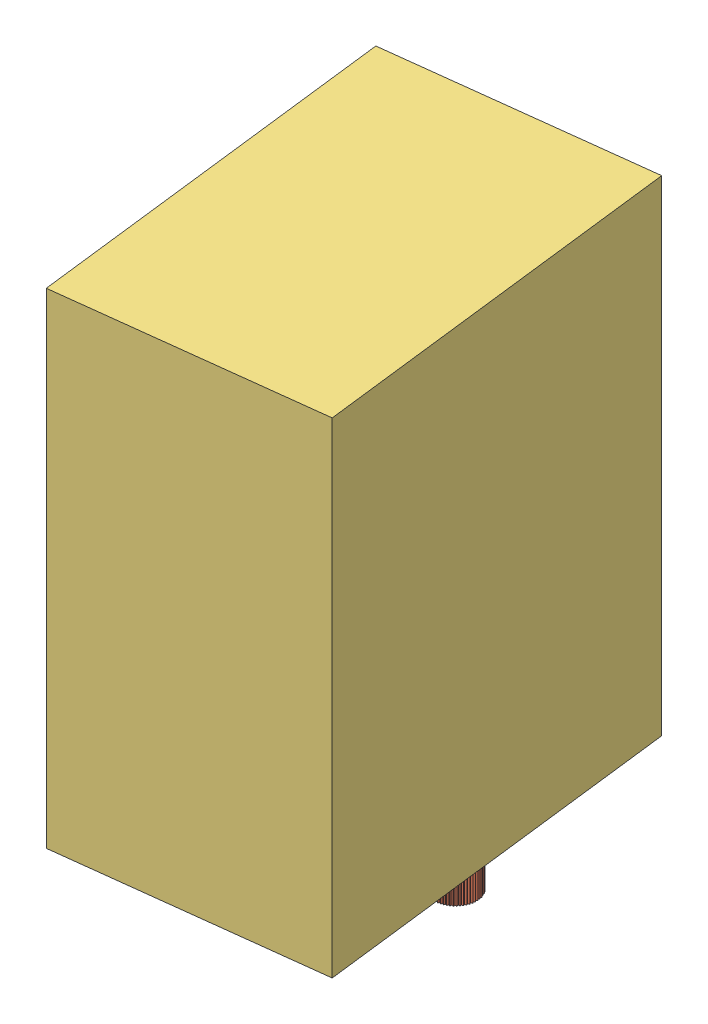
SolidWorks assembly Assembly for real, configuration Default. Lengths in mm.
Overall size (61.91 127.5 83.55).
4 component instances, 4 part files, 6 mates.
Components (placement in the parent):
- realpart-1: realpart [Default] at (4.0864 26.7845 46.9206) size (22.37 37 22.37)
- SmallerGear-1: SmallerGear [Default] at (2.4247 12.2845 33.1002) x (0.936342 0 -0.351089) z (0 -1 0) size (16 16 34.5)
- dstarrcomp-1: dstarrcomp [Default] at (9.5028 5.2845 91.9694) x (0 1 0) z (0.119374 0 0.992849) size (100 53 77.78)
- cover-1: cover [Default] at (-9.7757 45.7845 40.5297) x (0 -1 0) z (-0.992849 0 0.119374) size (22 20 37.19)
Mates (geometry in assembly coordinates):
- Concentric1: concentric anti-aligned: cylinder of realpart-1 through (4.0864 46.7845 46.9206) axis (0 -1 0) radius 8; cylinder of dstarrcomp-1 through (4.0864 23.7845 46.9206) axis (0 1 0) radius 8
- Coincident1: coincident anti-aligned: plane of realpart-1 through (4.0864 42.7845 46.9206) normal (0 1 0); plane of dstarrcomp-1 through (30.0407 42.7845 89.5001) normal (0 -1 0)
- Coincident2: coincident anti-aligned: plane of SmallerGear-1 through (2.4247 7.7845 33.1002) normal (0 -1 0); plane of dstarrcomp-1 through (-19.9002 7.7845 92.9867) normal (0 1 0)
- Concentric3: concentric aligned: cylinder of SmallerGear-1 through (2.4247 -22.2155 33.1002) axis (0 1 0) radius 4; cylinder of dstarrcomp-1 through (2.4247 5.2845 33.1002) axis (0 1 0) radius 4.5
- Coincident6: coincident anti-aligned: plane of dstarrcomp-1 through (23.6693 5.2845 36.5085) normal (-0.119374 0 -0.992849); plane of cover-1 through (-9.7757 45.7845 40.5297) normal (0.119374 0 0.992849)
- Coincident7: coincident anti-aligned: plane of realpart-1 through (4.0864 42.7845 46.9206) normal (0 1 0); plane of cover-1 through (5.0414 42.7845 54.8634) normal (0 -1 0)
